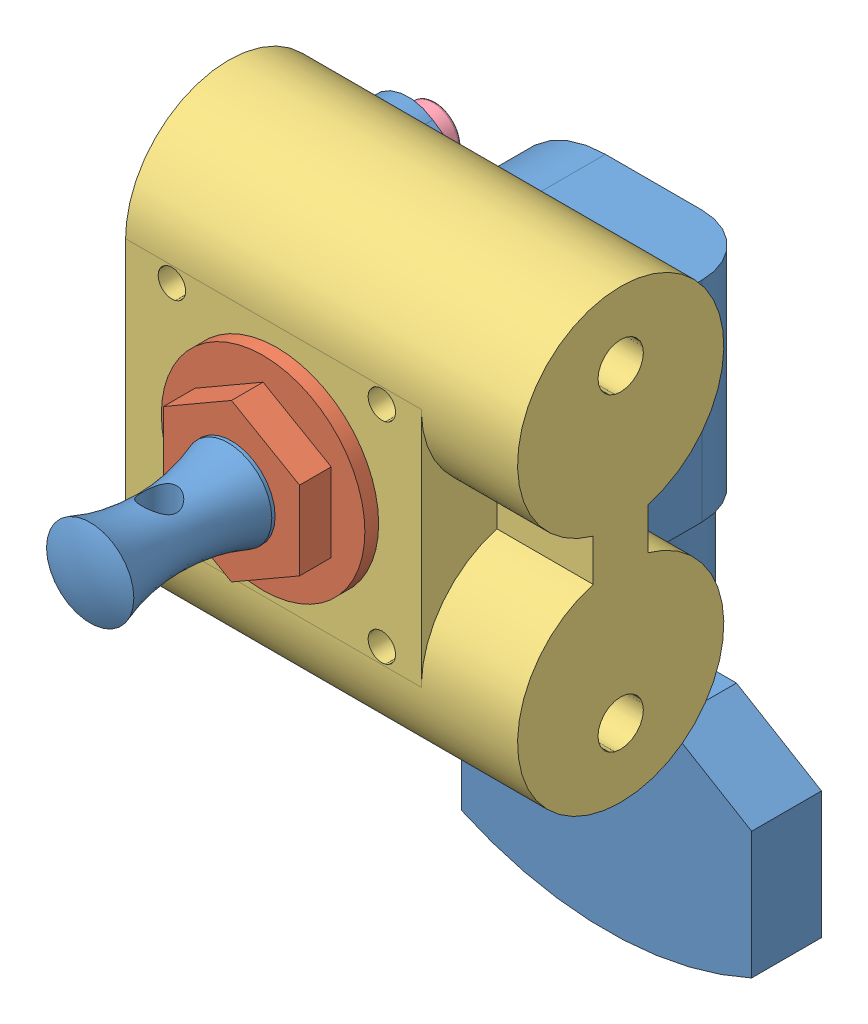
SolidWorks assembly tuning peg tensioner, configuration Default. Lengths in mm.
Overall size (28.57 50.54 38.1).
4 component instances, 4 part files, 9 mates.
Components (placement in the parent):
- TUNING PEG-1: TUNING PEG [Default] at origin size (28.38 45.1 38.1)
- TUNING PEG RETAINER-1: TUNING PEG RETAINER [Default] at (0 0 12.74) x (0 -1 0) z (0 0 1) size (14.8 14.8 14.45)
- tuning peg mount-1: tuning peg mount [Default] at (-0.0002 0.0002 8.89) x (-1 0 0) z (0 -1 0) size (28.5 15 32.5)
- M2X10-1: M2X10 [Default] at (-7.6332 7.6332 6.731) x (0 0 1) z (1 0 0) size (12 3.8 3.8)
Mates (geometry in assembly coordinates):
- Concentric116: concentric anti-aligned: cylinder of TUNING PEG-1 through (0 0 8.89) axis (0 0 1) radius 5.08; cylinder of tuning peg mount-1 through (-0.0002 0.0002 38.89) axis (0 0 -1) radius 5.08
- Coincident205: coincident anti-aligned: plane of TUNING PEG-1 through (3.8845 0 8.89) normal (0 0 1); plane of tuning peg mount-1 through (-0.0002 0.0002 8.89) normal (0 0 -1)
- Concentric118: concentric: cylinder of TUNING PEG-1 through (0 0 23.241) axis (0 0 -1) radius 3.175; cylinder of TUNING PEG RETAINER-1 through (0 0 12.74) axis (0 0 1) radius 3.125
- Concentric119: concentric anti-aligned: cylinder of TUNING PEG-1 through (-7.6332 7.6332 8.89) axis (0 0 -1) radius 1.125; cylinder of M2X10-1 through (-7.6332 7.6332 12.2537) axis (0 0 1) radius 1
- Coincident207: coincident anti-aligned: plane of TUNING PEG-1 through (-6.8243 6.8243 6.731) normal (0 0 -1); plane of M2X10-1 through (-7.6332 6.1832 6.731) normal (0 0 1)
- Coincident208: coordinate: point of TUNING PEG-1; point of assembly
- Parallel1: parallel anti-aligned: plane of TUNING PEG RETAINER-1 through (4.95 2.8579 27.19) normal (1 0 0); plane of tuning peg mount-1 through (-11.0002 -16.2498 8.89) normal (-1 0 0)
- Concentric120: concentric aligned: cylinder of TUNING PEG-1 through (-7.6332 7.6332 8.89) axis (0 0 -1) radius 1.125; cylinder of tuning peg mount-1 through (-7.6332 7.6332 23.89) axis (0 0 -1) radius 1
- Coincident209: coincident: plane of TUNING PEG RETAINER-1 through (0 0 23.89) normal (0 0 -1); plane of tuning peg mount-1 through (-0.0002 0.0002 23.89) normal (0 0 1)
